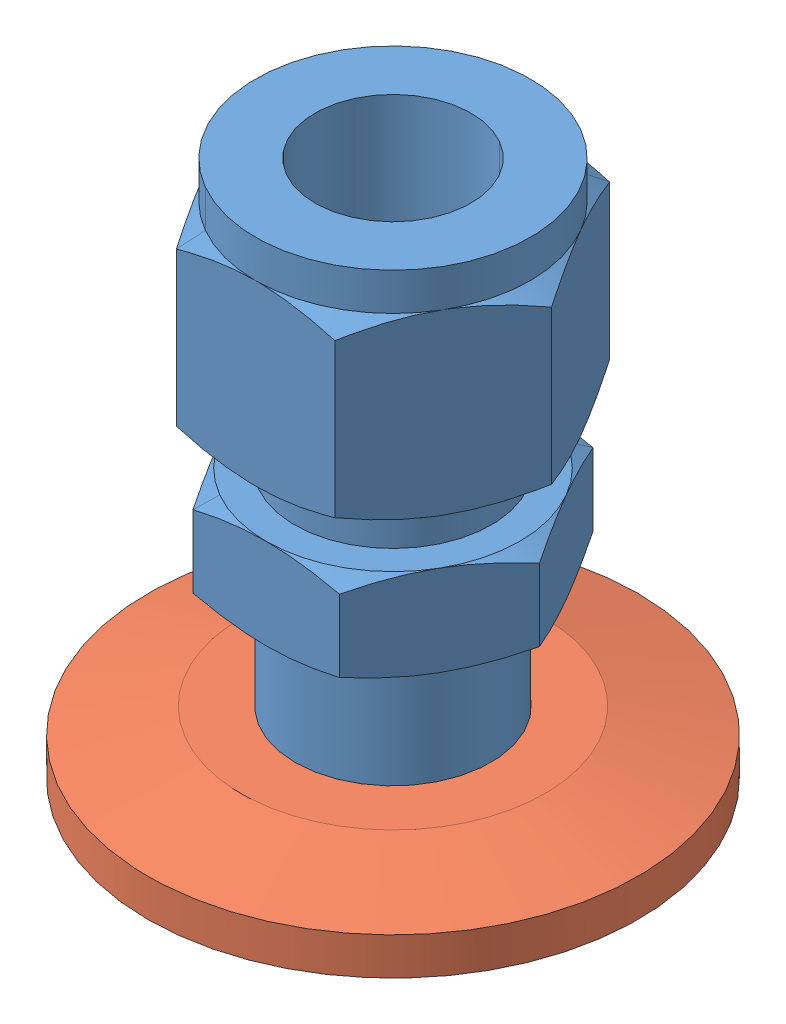
SolidWorks assembly 414016, configuration Default. Lengths in mm.
Overall size (39.88 43.69 39.88).
2 component instances, 2 part files, 6 mates.
Components (placement in the parent):
- 941402-02-1: 941402-02 [Default] at (0 43.688 0) x (0 -1 0) z (-0.5 0 0.866025) size (41.91 22.35 25.81)
- 961043-2: 961043 [Default] at (0 5.08 0) x (0 -1 0) z (0 0 1) size (5.08 39.88 39.88)
Mates (geometry in assembly coordinates):
- Coincident1: coincident anti-aligned: plane of 961043-2 through (19.939 0 0) normal (0 -1 0)
- Coincident2: coincident aligned: plane of 961043-2 through (0 5.08 0) normal (0 0 1)
- Coincident3: coincident aligned: plane of 961043-2 through (0 5.08 0) normal (1 0 0)
- Concentric2: concentric anti-aligned: cylinder of 941402-02-1 through (1.4031 7.6068 0) axis (0 -1 0) radius 7.9375; cylinder of 961043-2 through (0 5.08 0) axis (0 1 0) radius 7.9629
- Coincident4: coincident aligned: plane of 941402-02-1 through (1.4031 -29.3398 0) normal (0 -1 0); plane of 961043-2 through (8.7249 1.778 0) normal (0 -1 0)
- Parallel1: parallel aligned: line of 941402-02-1 through (4.845 -4.9558 12.4375) axis (-0.250915 0 0.968009)
